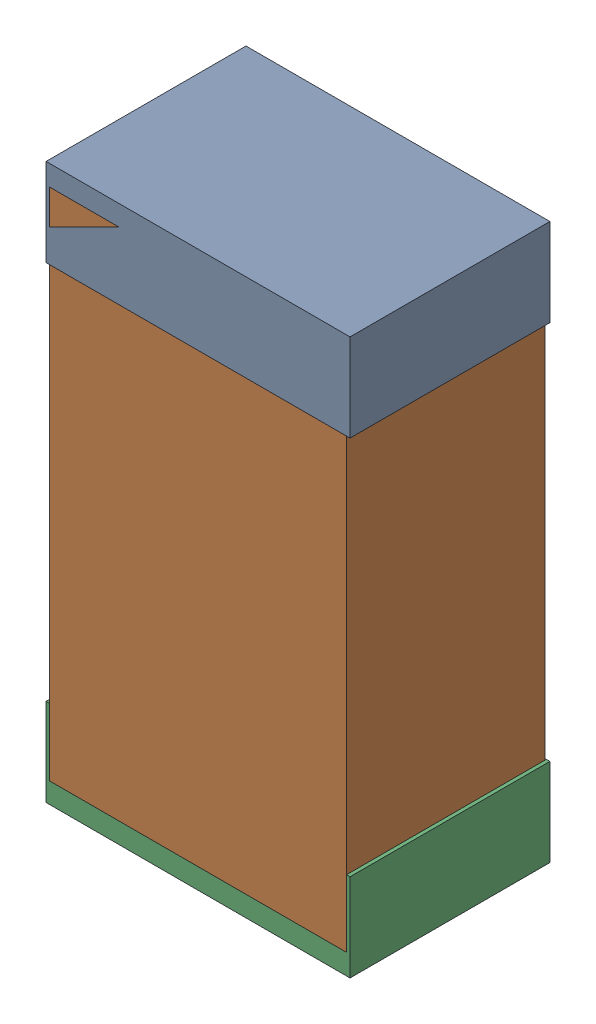
SolidWorks assembly R55Kanaloa_v2.0.0_Motor, configuration Default. Lengths in mm.
Overall size (1.3 2.38 0.85).
6 component instances, 2 part files, 0 mates.
Components (placement in the parent):
- 330415056-1: 330415056 [Default] at (136.398 155.686 -1.9574) size (1.3 0.38 0.85)
  - Extruded_2-1: Extruded_2 [Default] at origin size (1.3 0.38 0.85)
- 334787376-1: 334787376 [Default] at (136.398 154.686 -1.9524) size (1.27 2.2 0.85)
  - Extruded_16-1: Extruded_16 [Default] at origin size (1.27 2.2 0.85)
- 330415056-2: 330415056 [Default] at (136.398 153.686 -1.9574) size (1.3 0.38 0.85)
  - Extruded_2-1: Extruded_2 [Default] at origin size (1.3 0.38 0.85)
